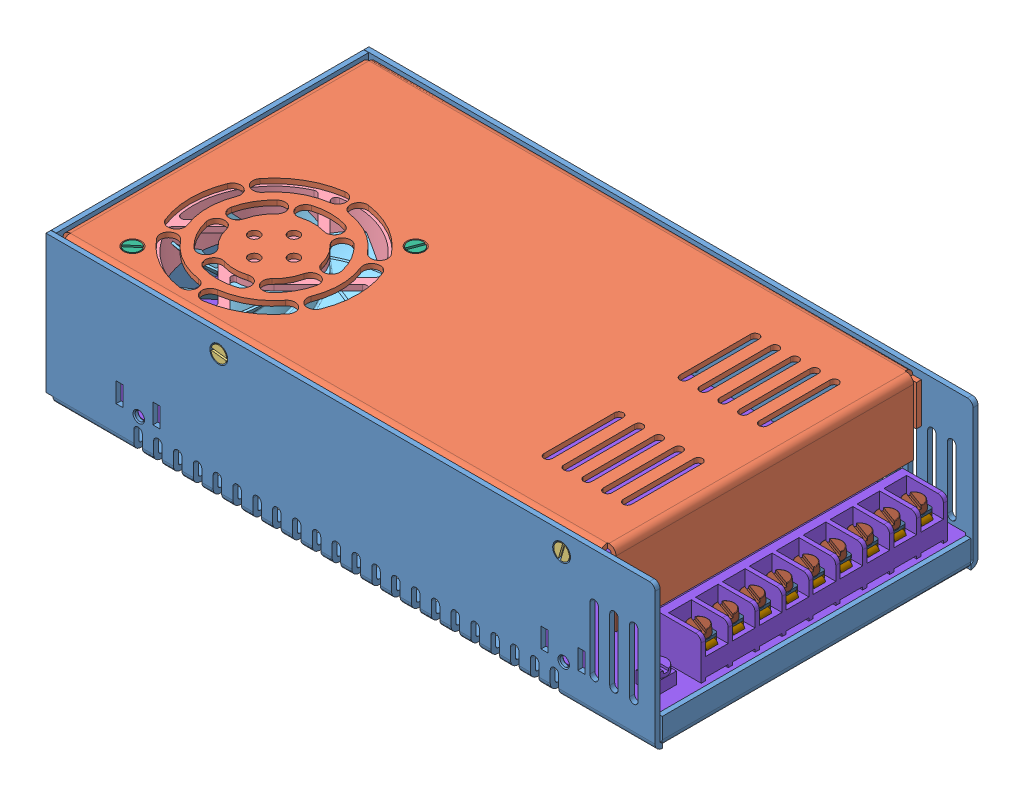
SolidWorks assembly Switching power supply, configuration Default. Lengths in mm.
Overall size (215 51.25 117.38).
46 component instances, 12 part files, 0 mates.
Components (placement in the parent):
- SWP (Basis)-1: SWP (Basis) [Default] at (0 1.75 57) x (1 0 0) z (0 1 0) size (215 114 51.25)
- SWP (Deksel)-1: SWP (Deksel) [Default] at (-18.25 51.25 57) x (1 0 0) z (0 1 0) size (195 110.5 25.75)
- Slotted Countersunk Flat Head Screw_DIN_ISO 2009 - M3 x 5 --- 5N-1: Slotted Countersunk Flat Head Screw_DIN_ISO 2009 - M3 x 5 --- 5N [Default] at (-154 44.75 114) x (0 0 -1) z (-0.992092 0.125515 0) size (5 5.5 5.44)
- Slotted Countersunk Flat Head Screw_DIN_ISO 2009 - M3 x 5 --- 5N-2: Slotted Countersunk Flat Head Screw_DIN_ISO 2009 - M3 x 5 --- 5N [Default] at (-33 44.75 114) x (0 0 -1) z (0.278156 0.960536 0) size (5 5.5 5.44)
- Slotted Countersunk Flat Head Screw_DIN_ISO 2009 - M3 x 5 --- 5N-3: Slotted Countersunk Flat Head Screw_DIN_ISO 2009 - M3 x 5 --- 5N [Default] at (-154 44.75 0) x (0 0 1) z (0 1 0) size (5 5.5 5.44)
- Slotted Countersunk Flat Head Screw_DIN_ISO 2009 - M3 x 5 --- 5N-4: Slotted Countersunk Flat Head Screw_DIN_ISO 2009 - M3 x 5 --- 5N [Default] at (-33 44.75 0) x (0 0 1) z (-0.877705 -0.479201 0) size (5 5.5 5.44)
- Slotted Countersunk Flat Head Screw_DIN_ISO 2009 - M3 x 5 --- 5N-5: Slotted Countersunk Flat Head Screw_DIN_ISO 2009 - M3 x 5 --- 5N [Default] at (-215 44.75 102) x (1 0 0) z (0 0.869235 -0.494399) size (5 5.5 5.44)
- Slotted Countersunk Flat Head Screw_DIN_ISO 2009 - M3 x 5 --- 5N-6: Slotted Countersunk Flat Head Screw_DIN_ISO 2009 - M3 x 5 --- 5N [Default] at (-215 44.75 12) x (1 0 0) z (0 0.76206 0.647506) size (5 5.5 5.44)
- Body 60mm fan-1: Body 60mm fan [Default] at (-170.75 34.3 77.75) x (1 0 0) z (0 1 0) size (59.5 59.5 15.2)
- Propellor 60mm fan-1: Propellor 60mm fan [Default] at (-170.75 44.3 77.75) x (0.544808 0 -0.838561) z (0 1 0) size (57.61 57.23 10.49)
- Slotted Countersunk Flat Head Screw_DIN_ISO 2009 - M3 x 20 --- 20N-1: Slotted Countersunk Flat Head Screw_DIN_ISO 2009 - M3 x 20 --- 20N [Default] at (-145.75 51.25 52.75) x (0 -1 0) z (0.364765 0 -0.9311) size (20 5.5 5.44)
- Slotted Countersunk Flat Head Screw_DIN_ISO 2009 - M3 x 20 --- 20N-2: Slotted Countersunk Flat Head Screw_DIN_ISO 2009 - M3 x 20 --- 20N [Default] at (-195.75 51.25 102.75) x (0 -1 0) z (0.762204 0 -0.647337) size (20 5.5 5.44)
- SWP (M3 moer)-1: SWP (M3 moer) [Default] at (-205 0 104.5) x (1 0 0) z (0 1 0) size (8.08 7 3.75)
- SWP (M3 moer)-2: SWP (M3 moer) [Default] at (-205 0 9.5) x (1 0 0) z (0 1 0) size (8.08 7 3.75)
- SWP (M3 moer)-3: SWP (M3 moer) [Default] at (-117.5 0 50.05) x (1 0 0) z (0 1 0) size (8.08 7 3.75)
- SWP (M3 moer)-4: SWP (M3 moer) [Default] at (-27.5 0 104.5) x (1 0 0) z (0 1 0) size (8.08 7 3.75)
- SWP (M3 moer)-5: SWP (M3 moer) [Default] at (-27.5 0 9.5) x (1 0 0) z (0 1 0) size (8.08 7 3.75)
- SWP (PCB)-1: SWP (PCB) [Default] at (-1.75 9.75 57) x (1 0 0) z (0 1 0) size (211.5 110.5 15.9)
- SWP (Montage draad)-1: SWP (Montage draad) [Default] at (-9.8 18.4 88.95) x (0 0 1) z (0 1 0) size (7 9.9 4.25)
- SWP (Montage draad 2)-1: SWP (Montage draad 2) [Default] at (-9.8 18.4 88.95) x (1 0 0) z (0 1 0) size (7 7 1)
- Slotted Cheese Head Screw_DIN_ISO 1207 - M4 x 5 --- 5N-1: Slotted Cheese Head Screw_DIN_ISO 1207 - M4 x 5 --- 5N [Default] at (-9.8 22 88.95) x (0 -1 0) z (0.939291 0 0.343123) size (7.61 7 7)
- SWP (Montage draad)-2: SWP (Montage draad) [Default] at (-9.8 18.4 79.45) x (0 0 1) z (0 1 0) size (7 9.9 4.25)
- SWP (Montage draad)-3: SWP (Montage draad) [Default] at (-9.8 18.4 69.95) x (0 0 1) z (0 1 0) size (7 9.9 4.25)
- SWP (Montage draad)-4: SWP (Montage draad) [Default] at (-9.8 18.4 60.45) x (0 0 1) z (0 1 0) size (7 9.9 4.25)
- SWP (Montage draad)-5: SWP (Montage draad) [Default] at (-9.8 18.4 50.95) x (0 0 1) z (0 1 0) size (7 9.9 4.25)
- SWP (Montage draad)-6: SWP (Montage draad) [Default] at (-9.8 18.4 41.45) x (0 0 1) z (0 1 0) size (7 9.9 4.25)
- SWP (Montage draad)-7: SWP (Montage draad) [Default] at (-9.8 18.4 31.95) x (0 0 1) z (0 1 0) size (7 9.9 4.25)
- SWP (Montage draad)-8: SWP (Montage draad) [Default] at (-9.8 18.4 22.45) x (0 0 1) z (0 1 0) size (7 9.9 4.25)
- SWP (Montage draad)-9: SWP (Montage draad) [Default] at (-9.8 18.4 12.95) x (0 0 1) z (0 1 0) size (7 9.9 4.25)
- SWP (Montage draad 2)-2: SWP (Montage draad 2) [Default] at (-9.8 18.4 79.45) x (1 0 0) z (0 1 0) size (7 7 1)
- SWP (Montage draad 2)-3: SWP (Montage draad 2) [Default] at (-9.8 18.4 69.95) x (1 0 0) z (0 1 0) size (7 7 1)
- SWP (Montage draad 2)-4: SWP (Montage draad 2) [Default] at (-9.8 18.4 60.45) x (1 0 0) z (0 1 0) size (7 7 1)
- SWP (Montage draad 2)-5: SWP (Montage draad 2) [Default] at (-9.8 18.4 50.95) x (1 0 0) z (0 1 0) size (7 7 1)
- SWP (Montage draad 2)-6: SWP (Montage draad 2) [Default] at (-9.8 18.4 41.45) x (1 0 0) z (0 1 0) size (7 7 1)
- SWP (Montage draad 2)-7: SWP (Montage draad 2) [Default] at (-9.8 18.4 31.95) x (1 0 0) z (0 1 0) size (7 7 1)
- SWP (Montage draad 2)-8: SWP (Montage draad 2) [Default] at (-9.8 18.4 22.45) x (1 0 0) z (0 1 0) size (7 7 1)
- SWP (Montage draad 2)-9: SWP (Montage draad 2) [Default] at (-9.8 18.4 12.95) x (1 0 0) z (0 1 0) size (7 7 1)
- Slotted Cheese Head Screw_DIN_ISO 1207 - M4 x 5 --- 5N-2: Slotted Cheese Head Screw_DIN_ISO 1207 - M4 x 5 --- 5N [Default] at (-9.8 22 79.45) x (0 -1 0) z (0.939291 0 0.343123) size (7.61 7 7)
- Slotted Cheese Head Screw_DIN_ISO 1207 - M4 x 5 --- 5N-3: Slotted Cheese Head Screw_DIN_ISO 1207 - M4 x 5 --- 5N [Default] at (-9.8 22 69.95) x (0 -1 0) z (0.939291 0 0.343123) size (7.61 7 7)
- Slotted Cheese Head Screw_DIN_ISO 1207 - M4 x 5 --- 5N-4: Slotted Cheese Head Screw_DIN_ISO 1207 - M4 x 5 --- 5N [Default] at (-9.8 22 60.45) x (0 -1 0) z (0.939291 0 0.343123) size (7.61 7 7)
- Slotted Cheese Head Screw_DIN_ISO 1207 - M4 x 5 --- 5N-5: Slotted Cheese Head Screw_DIN_ISO 1207 - M4 x 5 --- 5N [Default] at (-9.8 22 50.95) x (0 -1 0) z (0.939291 0 0.343123) size (7.61 7 7)
- Slotted Cheese Head Screw_DIN_ISO 1207 - M4 x 5 --- 5N-6: Slotted Cheese Head Screw_DIN_ISO 1207 - M4 x 5 --- 5N [Default] at (-9.8 22 41.45) x (0 -1 0) z (0.939291 0 0.343123) size (7.61 7 7)
- Slotted Cheese Head Screw_DIN_ISO 1207 - M4 x 5 --- 5N-7: Slotted Cheese Head Screw_DIN_ISO 1207 - M4 x 5 --- 5N [Default] at (-9.8 22 31.95) x (0 -1 0) z (0.939291 0 0.343123) size (7.61 7 7)
- Slotted Cheese Head Screw_DIN_ISO 1207 - M4 x 5 --- 5N-8: Slotted Cheese Head Screw_DIN_ISO 1207 - M4 x 5 --- 5N [Default] at (-9.8 22 22.45) x (0 -1 0) z (0.939291 0 0.343123) size (7.61 7 7)
- Slotted Cheese Head Screw_DIN_ISO 1207 - M4 x 5 --- 5N-9: Slotted Cheese Head Screw_DIN_ISO 1207 - M4 x 5 --- 5N [Default] at (-9.8 22 12.95) x (0 -1 0) z (0.939291 0 0.343123) size (7.61 7 7)
- SWP (switch)-1: SWP (switch) [Default] at (-128.5 14.3 0) x (-1 0 0) z (0 0 -1) size (19 12.1 6)
